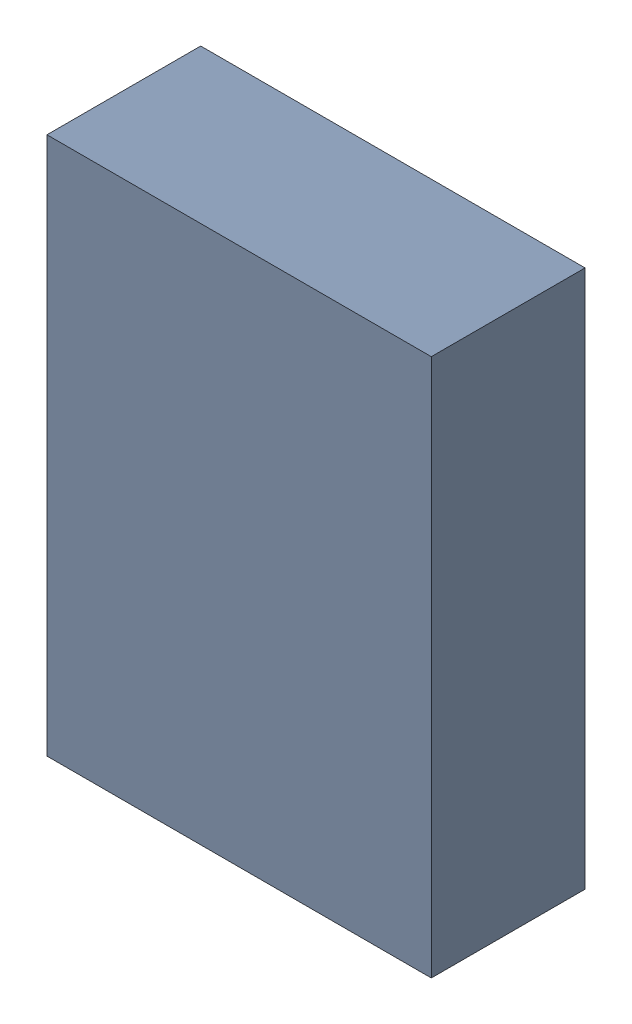
SolidWorks assembly Kanaloa_v2.0.0_Loko_8, configuration Default. Lengths in mm.
Overall size (2.5 3.5 1).
2 component instances, 1 part files, 0 mates.
Components (placement in the parent):
- 378153280_1-1: 378153280_1 [Default] at (58.932 74.8538 0) size (2.5 3.5 1)
  - Extruded_33-1: Extruded_33 [Default] at origin size (2.5 3.5 1)
